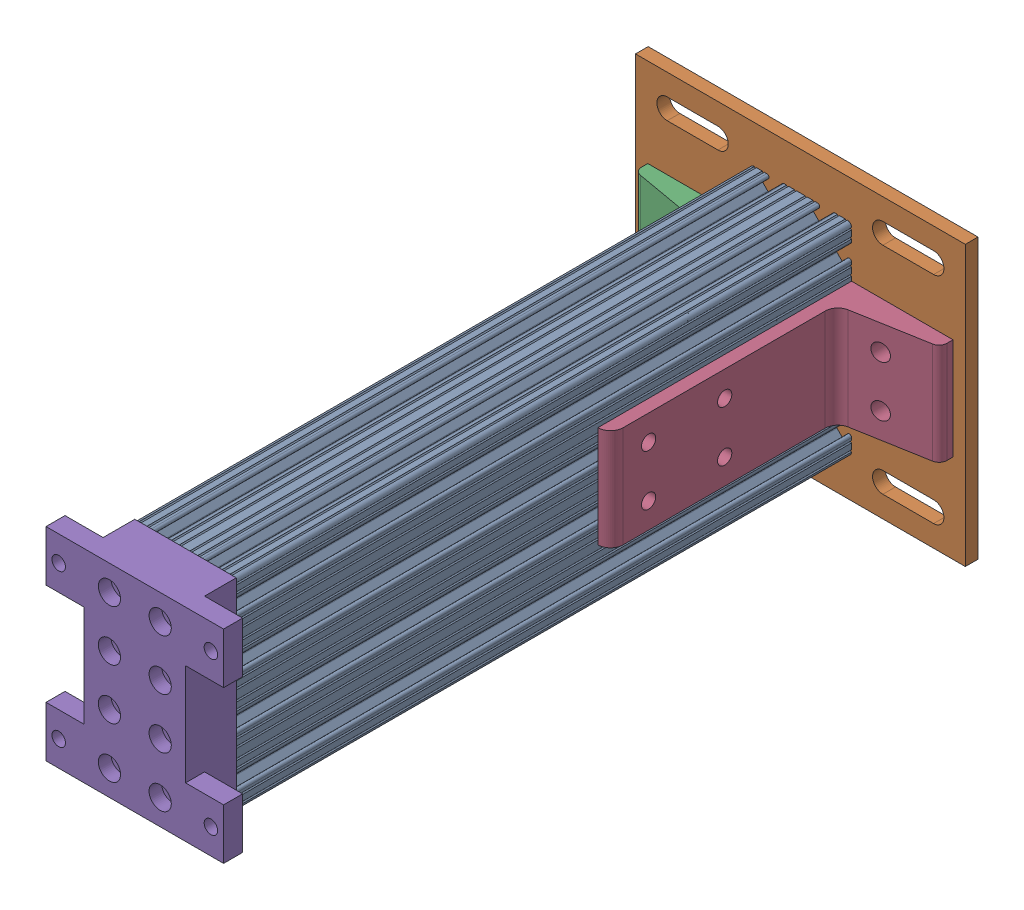
SolidWorks assembly Mirrorbreadboard support leg assembly2, configuration Default. Lengths in mm.
Overall size (165.1 139.7 339.72).
6 component instances, 4 part files, 6 mates.
Components (placement in the parent):
- Mirror8020-2040 leg for breadboard support-1: Mirror8020-2040 leg for breadboard support [Default] at (-48.9055 -77.0614 -78.1612) size (50.8 101.6 307.98)
- Mirror8020-2387-DEFAULT2-1: Mirror8020-2387-DEFAULT2 [Default] at (-34.9863 -22.6888 -91.8816) x (0 1 0) z (1 0 0) size (139.7 133.35 165.1)
  - Mirror8020-2387-DEFAULT_238708-1: Mirror8020-2387-DEFAULT_238708 [Default] at (-67.1549 7.3704 -27.8119) size (139.7 6.35 165.1)
  - Mirror8020-2387-DEFAULT_238509-1: Mirror8020-2387-DEFAULT_238509 [Default] at (9.1264 0.0214 -49.7635) x (0 0 -1) z (1 0 0) size (50.8 127 50.8)
  - Mirror8020-2387-DEFAULT_238509-2: Mirror8020-2387-DEFAULT_238509 [Default] at (-41.6736 0.0214 46.9187) x (0 0 1) z (-1 0 0) size (50.8 127 50.8)
- Mirrorbreadboard support leg top bracket-1: Mirrorbreadboard support leg top bracket [Default] at (-61.6055 -89.7614 229.8138) x (0 1 0) z (1 0 0) size (101.6 25.4 88.9)
Mates (geometry in assembly coordinates):
- Coincident1: coincident anti-aligned: plane of Mirror8020-2040 leg for breadboard support-1 through (-61.6055 -36.3198 -78.1612) normal (0 0 -1); plane of Mirror8020-2387-DEFAULT2-1/Mirror8020-2387-DEFAULT_238708-1 through (-36.4088 -207.3239 -78.1612) normal (0 0 1)
- Coincident2: coincident anti-aligned: plane of Mirror8020-2040 leg for breadboard support-1 through (-10.8056 -41.095 229.8138) normal (1 0 0); plane of Mirror8020-2387-DEFAULT2-1/Mirror8020-2387-DEFAULT_238509-2 through (-10.8056 -13.5624 -150.9329) normal (-1 0 0)
- Distance1: distance = 19.05 mm aligned: plane of Mirror8020-2387-DEFAULT2-1/Mirror8020-2387-DEFAULT_238708-1 through (-36.4088 -108.8114 -78.1612) normal (0 -1 0); plane of Mirror8020-2040 leg for breadboard support-1 through (-38.3391 -89.7614 229.8138) normal (0 -1 0)
- Coincident3: coincident anti-aligned: plane of Mirror8020-2040 leg for breadboard support-1 through (-61.6055 -36.3198 229.8138) normal (0 0 1); plane of Mirrorbreadboard support leg top bracket-1 through (-10.8055 -89.7614 229.8138) normal (0 0 -1)
- Concentric1: concentric anti-aligned: circle of Mirror8020-2040 leg for breadboard support-1; circle of Mirrorbreadboard support leg top bracket-1
- Concentric2: concentric anti-aligned: circle of Mirror8020-2040 leg for breadboard support-1; circle of Mirrorbreadboard support leg top bracket-1
